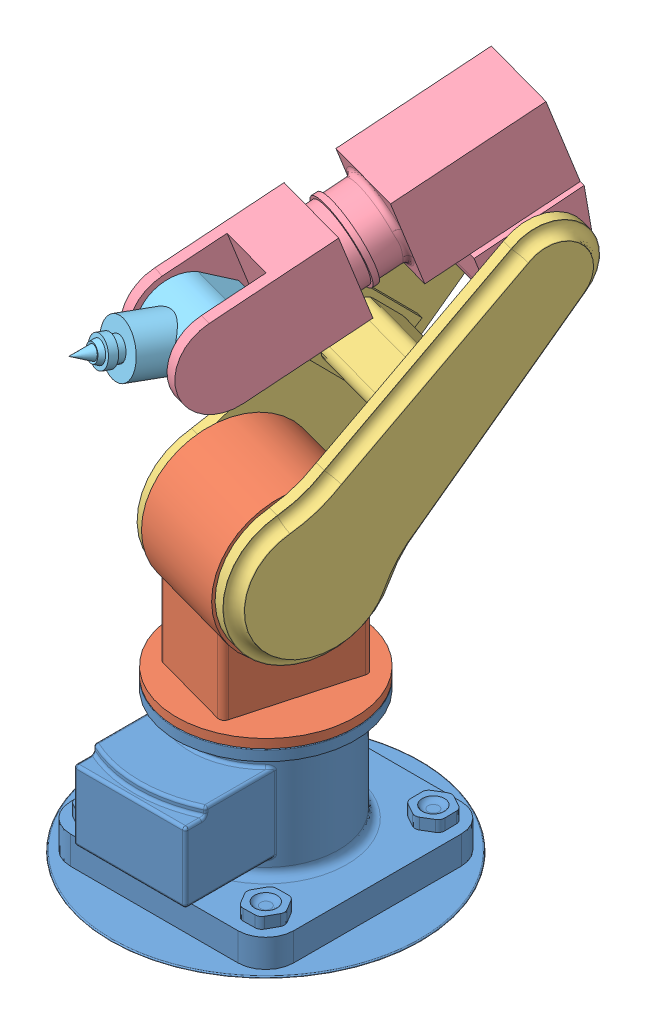
SolidWorks assembly Assem1, configuration Default. Lengths in mm.
Overall size (555 1085.93 816.31).
5 component instances, 5 part files, 8 mates.
Components (placement in the parent):
- Robotic Arm part 01-1: Robotic Arm part 01 [Default] at (229.6024 191.4838 480.8496) size (555 272.54 555)
- Robotic Arm Part2-1: Robotic Arm Part2 [Default] at (229.6024 344.0238 480.8496) x (0.265959 0 -0.963984) z (0.963984 0 0.265959) size (320 466 320)
- Robotic Arm Part3-2: Robotic Arm Part3 [Default] at (229.6024 680.0238 480.8496) x (0.190727 -0.696942 -0.691299) z (-0.185358 -0.717127 0.671842) size (250 260.14 700)
- Robotic Arm Part4-1: Robotic Arm Part4 [Default] at (342.272 1206.69 110.0721) x (-0.2508 -0.332792 0.909037) z (-0.963984 0 -0.265959) size (595 298.07 160)
- Robotic Arm Part5-1: Robotic Arm Part5 [Default] at (211.8561 1033.6382 582.7716) x (-0.261747 0.177285 0.948714) z (0.047151 0.98416 -0.1709) size (272.54 100 130)
Mates (geometry in assembly coordinates):
- Concentric1: concentric anti-aligned: cylinder of Robotic Arm part 01-1 through (229.6024 264.0238 480.8496) axis (0 1 0) radius 100; cylinder of Robotic Arm Part2-1 through (229.6024 464.0238 480.8496) axis (0 -1 0) radius 100
- Coincident1: coincident anti-aligned: plane of Robotic Arm part 01-1 through (229.6024 464.0238 480.8496) normal (0 1 0); plane of Robotic Arm Part2-1 through (229.6024 464.0238 480.8496) normal (0 -1 0)
- Coincident2: coincident anti-aligned: circle of Robotic Arm Part2-1; cylinder of Robotic Arm Part3-2 through (314.4291 680.0238 510.9231) axis (-0.94252 0 -0.33415) radius 75
- Coincident3: coincident anti-aligned: plane of Robotic Arm Part2-1 through (314.4291 680.0238 510.9231) normal (0.94252 0 0.33415); plane of Robotic Arm Part3-2 through (182.1995 985.648 883.8965) normal (-0.94252 0 -0.33415)
- Concentric2: concentric anti-aligned: cylinder of Robotic Arm Part3-2 through (182.1995 985.648 883.8965) axis (-0.94252 0 -0.33415) radius 50; cylinder of Robotic Arm Part4-1 through (31.3963 985.648 830.4325) axis (0.94252 0 0.33415) radius 50
- Coincident4: coincident anti-aligned: plane of Robotic Arm Part3-2; plane of Robotic Arm Part4-1
- Concentric3: concentric anti-aligned: cylinder of Robotic Arm Part4-1 through (-86.0598 1102.3459 1251.5147) axis (0.94252 0 0.33415) radius 50; cylinder of Robotic Arm Part5-1 through (8.1922 1102.3459 1284.9297) axis (-0.94252 0 -0.33415) radius 50
- Coincident5: coincident anti-aligned: plane of Robotic Arm Part4-1; plane of Robotic Arm Part5-1
